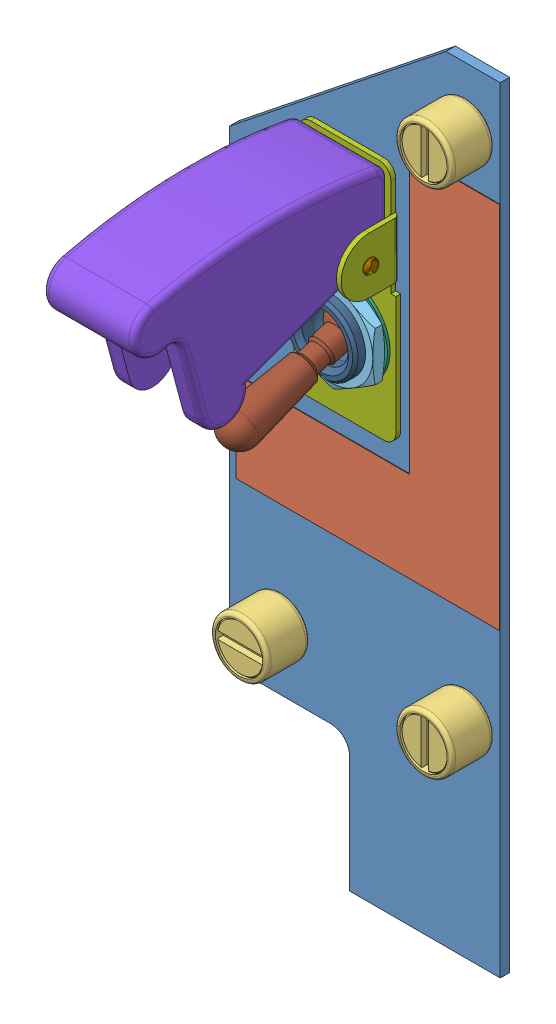
SolidWorks assembly GEN TIE Panel Ref, configuration Default. Lengths in mm.
Overall size (45.72 130.81 53.41).
16 component instances, 11 part files, 0 mates.
Components (placement in the parent):
- GEN TIE Mount Plate Ref-1: GEN TIE Mount Plate Ref [Default] at origin size (45.72 130.81 1.59)
- GEN TIE Sticker Ref-1: GEN TIE Sticker Ref [Default] at origin size (44.45 62.23 0.1)
- D5 DZUS Stud Ref v1-1: D5 DZUS Stud Ref v1 [Default] at (-5.715 34.925 1.5875) size (9.65 9.65 8.83)
- D5 DZUS Stud Ref v1-2: D5 DZUS Stud Ref v1 [Default] at (-36.83 33.3375 1.5875) x (0 1 0) z (0 0 1) size (9.65 9.65 8.83)
- D5 DZUS Stud Ref v1-3: D5 DZUS Stud Ref v1 [Default] at (-5.715 121.158 1.5875) size (9.65 9.65 8.83)
- MS25081-4 v1-1: MS25081-4 v1 [Default] at (-25.4 83.058 -1.016) x (-1 0 0) z (0 0 1) size (18.26 19.09 2.29)
- MS25082-8 v2-1: MS25082-8 v2 [Default] at (-25.4 83.058 -2.0066) size (15.08 16.48 1.98)
- MS35333-126 v1-1: MS35333-126 v1 [Default] at (-25.4 83.058 2.6161) size (15.24 15.24 0.71)
- Toggle Switch Guard Red v4-1: Toggle Switch Guard Red v4 [Default] at origin size (23.94 52.92 48.29)
  - ToggleBasePlate-1: ToggleBasePlate [Default] at (-34 69.558 1.5875) size (17.2 40.5 10)
  - Toggle switch cover-1: Toggle switch cover [Default] at (-17.65 100.4671 1.4582) x (0 -0.34202 0.939693) z (-1 0 0) size (41.56 27.01 15.51)
  - Toggle switch pin-1: Toggle switch pin [Default] at (-16.85 98.308 6.8375) x (0 -0.241147 0.970489) z (1 0 0) size (11.39 11.39 23.94)
- MS25082-8 v2-2: MS25082-8 v2 [Default] at (-25.4 83.058 3.8353) size (15.08 16.48 1.98)
- MS Toggle Switch Sealed 2-Position Ref v2-1: MS Toggle Switch Sealed 2-Position Ref v2 [Default] at origin size (14.29 17.66 30.89)
  - Toggle Threads Sealed Ref-1: Toggle Threads Sealed Ref [Default] at (-25.4 83.058 -5.3811) size (14.29 14.29 13.21)
  - Toggle Lever Sealed Ref-1: Toggle Lever Sealed Ref [Default] at (-25.4 84.7172 -5.1405) x (1 0 0) z (0 -0.284015 0.95882) size (10.67 7.94 27.59)
